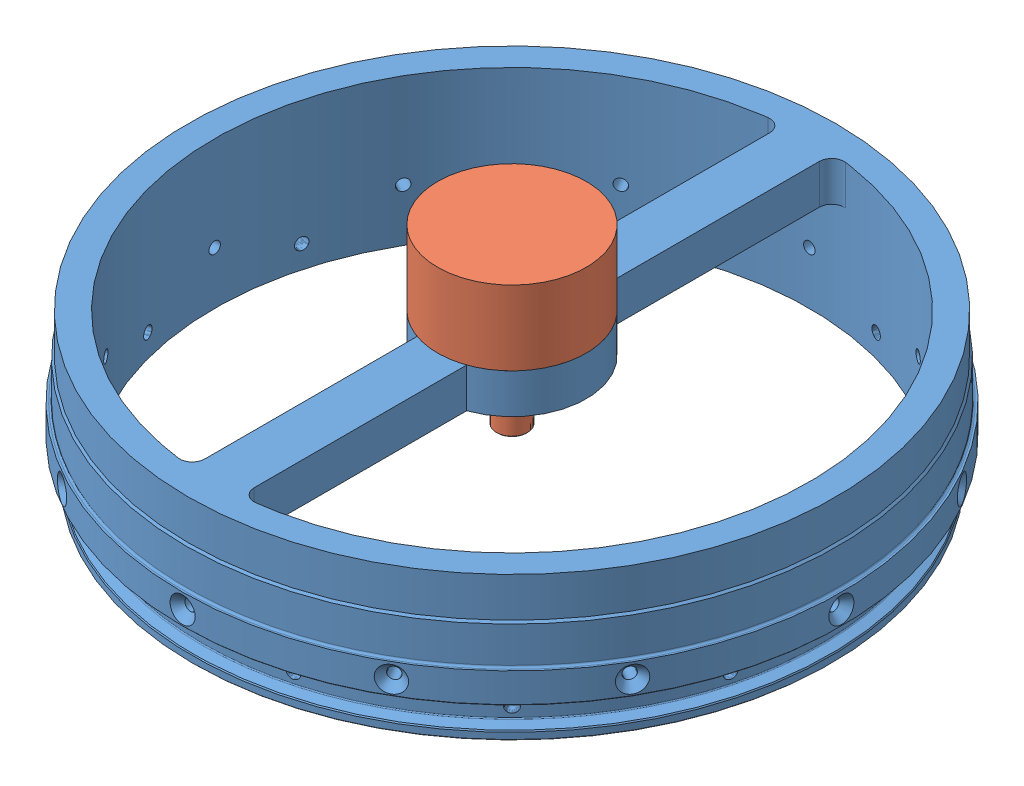
SolidWorks assembly Assem1, configuration Default. Lengths in mm.
Overall size (168.91 56.73 168.91).
2 component instances, 2 part files, 1 mates.
Components (placement in the parent):
- Concept_Upper-1: Concept_Upper [Default] at (-34.5539 6.0921 8.3984) size (168.91 37.68 168.91)
- pretend_motor-1: pretend_motor [Default] at (-34.5539 52.3686 8.3984) x (-0.837169 0 -0.546944) z (-0.546944 0 0.837169) size (38.1 44.45 38.1)
Mates (geometry in assembly coordinates):
- Concentric1: concentric: cylinder of Concept_Upper-1 through (-34.5539 23.1586 8.3984) axis (0 1 0) radius 19.05; cylinder of pretend_motor-1 through (-34.5539 33.3186 8.3984) axis (0 1 0) radius 19.05
